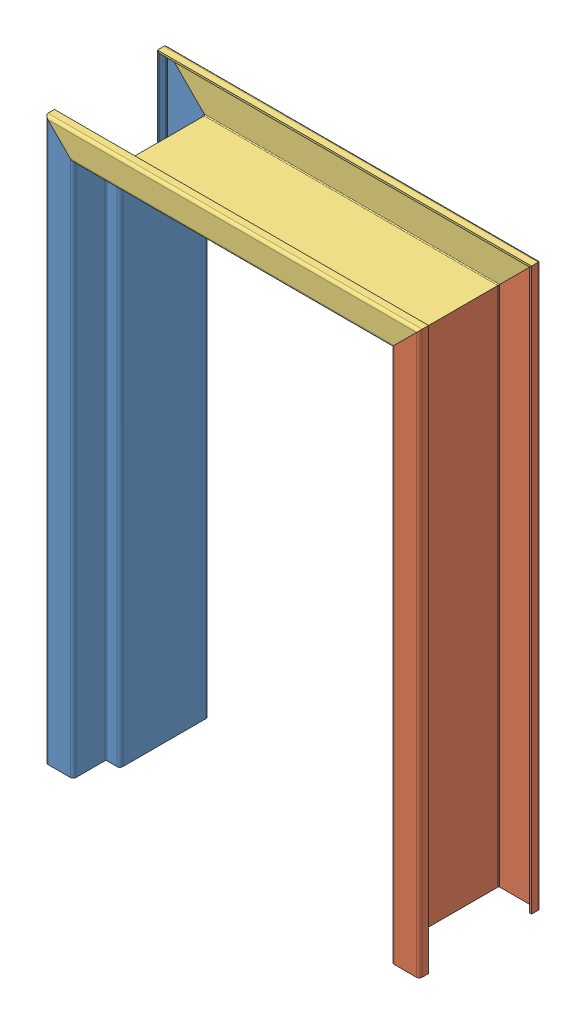
SolidWorks assembly zostava, configuration Výchozí. Lengths in mm.
Overall size (400 600 130).
3 component instances, 3 part files, 6 mates.
Components (placement in the parent):
- diel 1-1: diel 1 [Výchozia] at origin size (45 600 130)
- diel 2-1: diel 2 [Výchozia] at (355 0 0) size (45 600 130)
- diel 3-1: diel 3 [Výchozia] at (177.5 577.5 0) size (400 45 130)
Mates (geometry in assembly coordinates):
- Sjednocená1: coincident aligned: plane of diel 1-1 through (-19.5 600 65) normal (0 0 1); plane of diel 3-1 through (377.5 597 65) normal (0 0 1)
- Sjednocená2: coincident aligned: plane of diel 2-1 through (374.5 600 65) normal (0 0 1); plane of diel 3-1 through (377.5 597 65) normal (0 0 1)
- Sjednocená3: coincident anti-aligned: plane of diel 1-1 through (-22.5 600 -128.6396) normal (0.707107 0.707107 0); plane of diel 3-1 through (22.5 555 -128.6396) normal (-0.707107 -0.707107 0)
- Sjednocená4: coincident anti-aligned: plane of diel 2-1 through (332.5 555 -128.6396) normal (-0.707107 0.707107 0); plane of diel 3-1 through (332.5 555 -128.6396) normal (0.707107 -0.707107 0)
- Sjednocená5: coincident aligned: line of diel 1-1 through (-22.5 600 55) axis (0 0 1); line of diel 3-1 through (-22.5 600 55) axis (0 0 1)
- Sjednocená6: coincident aligned: line of diel 2-1 through (377.5 600 55) axis (0 0 1); line of diel 3-1 through (377.5 600 55) axis (0 0 1)
